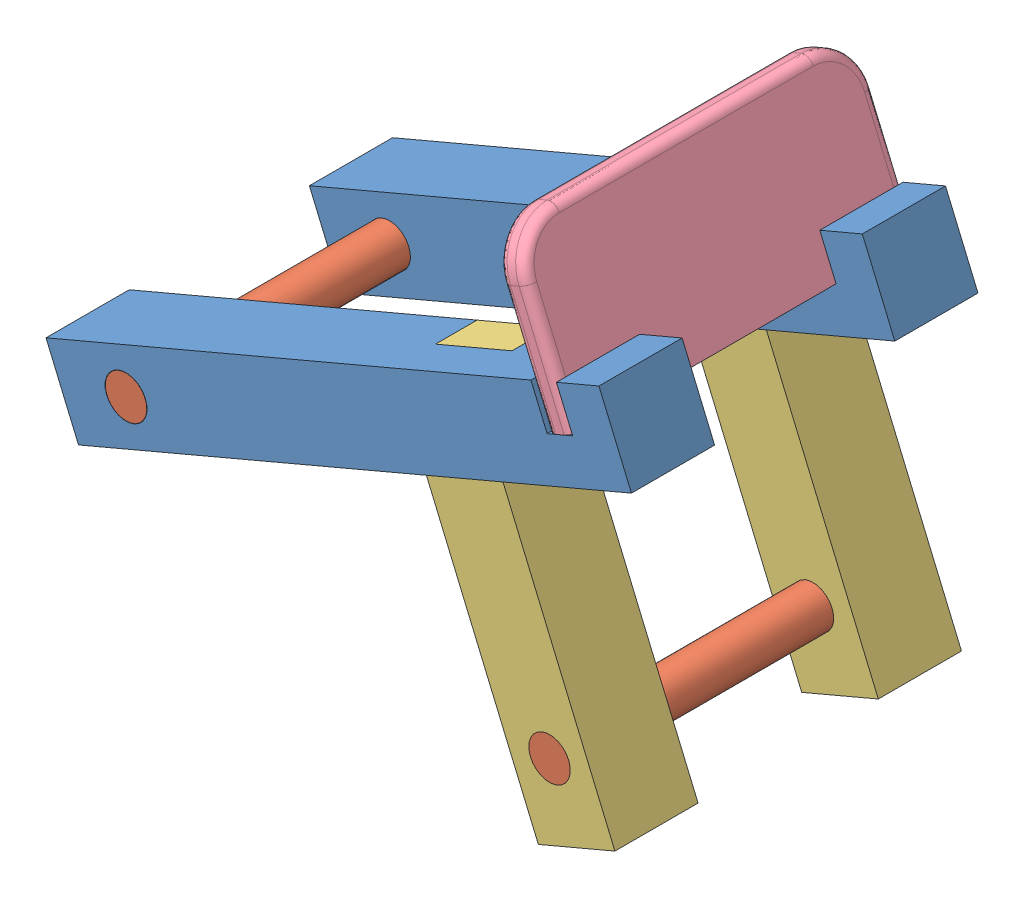
SolidWorks assembly Phone Holder Assembly, configuration Default. Lengths in mm.
Overall size (126.7 112.5 75).
7 component instances, 4 part files, 17 mates.
Components (placement in the parent):
- Long Piece-1: Long Piece [Default] at (115.1098 50.3541 68.0678) x (0.920505 0.390731 0) z (0 0 1) size (130 18 18)
- Long Piece-2: Long Piece [Default] at (115.1098 50.3541 11.0678) x (0.920505 0.390731 0) z (0 0 1) size (130 18 18)
- Dowel-1: Dowel [Default] at (5.7352 13.7045 11.0678) x (0 0 1) z (-0.444594 0.895732 0) size (75 9 9)
- Short Piece-1: Short Piece [Default] at (111.5322 -18.5189 86.0678) x (0.390731 -0.920505 0) z (0 0 -1) size (80 18 18)
- Short Piece-2: Short Piece [Default] at (111.5322 -18.5189 29.0678) x (0.390731 -0.920505 0) z (0 0 -1) size (80 18 18)
- Base Phone-1: Base Phone [Default] at (102.3882 54.7313 86.0678) x (0 0 1) z (0.390731 -0.920505 0) size (75 6 35)
- Dowel-2: Dowel [Default] at (97.3867 -8.2279 11.0678) x (0 0 1) z (-0.911852 0.410519 0) size (75 9 9)
Mates (geometry in assembly coordinates):
- Distance1: distance = 39 mm anti-aligned: plane of Long Piece-1 through (115.1098 50.3541 68.0678) normal (0 0 -1); plane of Long Piece-2 through (115.1098 50.3541 29.0678) normal (0 0 1)
- Coincident2: coincident aligned: plane of Long Piece-1 through (108.0767 66.9231 86.0678) normal (-0.390731 0.920505 0); plane of Long Piece-2 through (108.0767 66.9231 29.0678) normal (-0.390731 0.920505 0)
- Coincident3: coincident aligned: plane of Long Piece-1 through (-4.5558 -0.441 86.0678) normal (-0.920505 -0.390731 0); plane of Long Piece-2 through (-4.5558 -0.441 29.0678) normal (-0.920505 -0.390731 0)
- Concentric1: concentric aligned: cylinder of Long Piece-1 through (5.7352 13.7045 77.0678) axis (0 0 -1) radius 4.5; cylinder of Dowel-1 through (5.7352 13.7045 86.0678) axis (0 0 -1) radius 4.5
- Coincident4: coincident aligned: plane of Long Piece-2 through (115.1098 50.3541 11.0678) normal (0 0 -1); plane of Dowel-1 through (5.7352 13.7045 11.0678) normal (0 0 -1)
- Coincident5: coincident anti-aligned: plane of Long Piece-1 through (115.1098 50.3541 77.0678) normal (0 0 -1); plane of Short Piece-1 through (80.2737 55.1215 77.0678) normal (0 0 1)
- Coincident6: coincident anti-aligned: plane of Long Piece-1 through (63.7046 48.0883 77.0678) normal (0.920505 0.390731 0); plane of Short Piece-1 through (94.9631 -25.5521 68.0678) normal (-0.920505 -0.390731 0)
- Coincident7: coincident aligned: plane of Long Piece-1 through (108.0767 66.9231 86.0678) normal (-0.390731 0.920505 0); plane of Short Piece-1 through (80.2737 55.1215 68.0678) normal (-0.390731 0.920505 0)
- Coincident16: coincident anti-aligned: plane of Long Piece-2 through (80.2737 55.1215 20.0678) normal (-0.920505 -0.390731 0); plane of Short Piece-2 through (111.5322 -18.5189 11.0678) normal (0.920505 0.390731 0)
- Coincident17: coincident aligned: plane of Long Piece-2 through (108.0767 66.9231 29.0678) normal (-0.390731 0.920505 0); plane of Short Piece-2 through (80.2737 55.1215 11.0678) normal (-0.390731 0.920505 0)
- Coincident18: coincident anti-aligned: plane of Long Piece-2 through (115.1098 50.3541 20.0678) normal (0 0 -1); plane of Short Piece-2 through (80.2737 55.1215 20.0678) normal (0 0 1)
- Coincident19: coincident anti-aligned: plane of Long Piece-1 through (102.3882 54.7313 77.0678) normal (-0.390731 0.920505 0); plane of Base Phone-1 through (96.8652 52.3869 86.0678) normal (0.390731 -0.920505 0)
- Coincident20: coincident anti-aligned: plane of Long Piece-1 through (93.3486 60.6714 77.0678) normal (0.920505 0.390731 0); plane of Base Phone-1 through (87.0969 75.3995 76.0678) normal (-0.920505 -0.390731 0)
- Coincident21: coincident aligned: plane of Long Piece-2 through (115.1098 50.3541 11.0678) normal (0 0 -1); plane of Base Phone-1 through (96.8652 52.3869 11.0678) normal (0 0 -1)
- Concentric3: concentric aligned: cylinder of Short Piece-2 through (97.3867 -8.2279 20.0678) axis (0 0 -1) radius 4.5; cylinder of Dowel-2 through (97.3867 -8.2279 86.0678) axis (0 0 -1) radius 4.5
- Coincident25: coincident aligned: plane of Short Piece-1 through (111.5322 -18.5189 86.0678) normal (0 0 1); plane of Dowel-2 through (97.3867 -8.2279 86.0678) normal (0 0 1)
- Angle5: planar angle = 0.401426 rad anti-aligned: plane of assembly through (0 0 0) normal (0 1 0); plane of Long Piece-2 through (115.1098 50.3541 29.0678) normal (0.390731 -0.920505 0)
